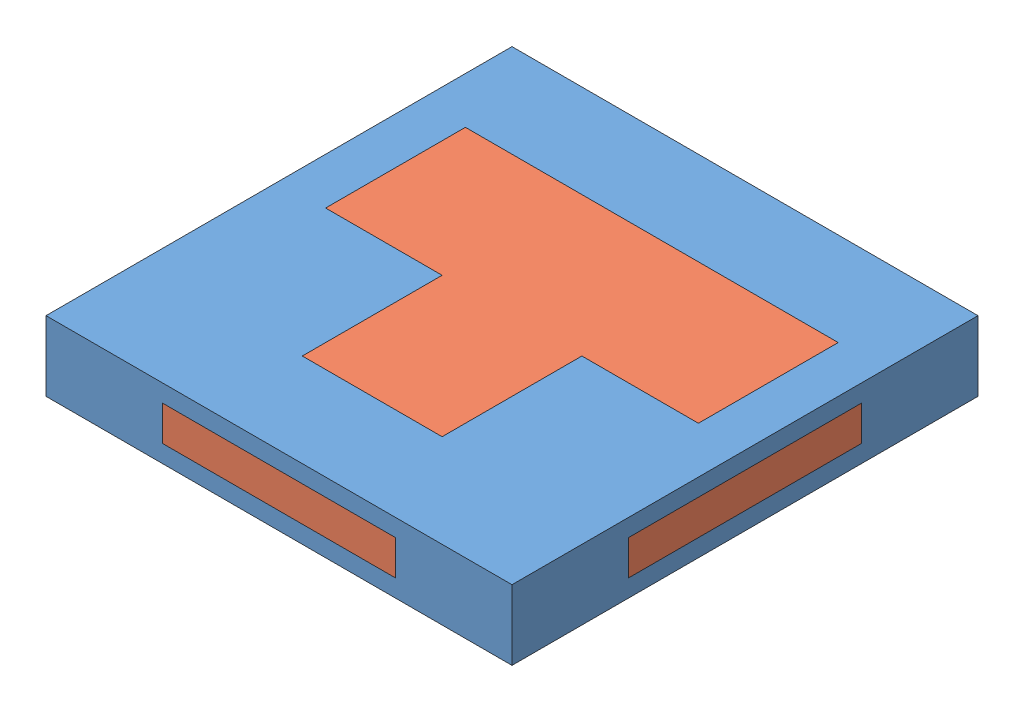
SolidWorks assembly Assem4, configuration Default. Lengths in mm.
Overall size (20 3 20).
2 component instances, 2 part files, 3 mates.
Components (placement in the parent):
- Tetris Outer-1: Tetris Outer [Default] at (7.6057 7.8169 16.0387) size (20 3 20)
- Tetris Inner-1: Tetris Inner [Default] at (7.6057 7.8169 16.0387) size (20 3 20)
Mates (geometry in assembly coordinates):
- Coincident1: coincident: plane of Tetris Outer-1 through (17.6057 10.8169 16.0387) normal (1 0 0); plane of Tetris Inner-1 through (17.6057 12.5574 16.0387) normal (1 0 0)
- Coincident2: coincident: plane of Tetris Outer-1 through (-2.3943 8.5669 11.0387) normal (0 0 1); plane of Tetris Inner-1 through (7.6057 12.5574 11.0387) normal (0 0 -1)
- Coincident3: coincident anti-aligned: plane of Tetris Outer-1 through (12.6057 10.0669 6.0387) normal (0 -1 0); plane of Tetris Inner-1 through (7.6057 10.0669 16.0387) normal (0 1 0)
